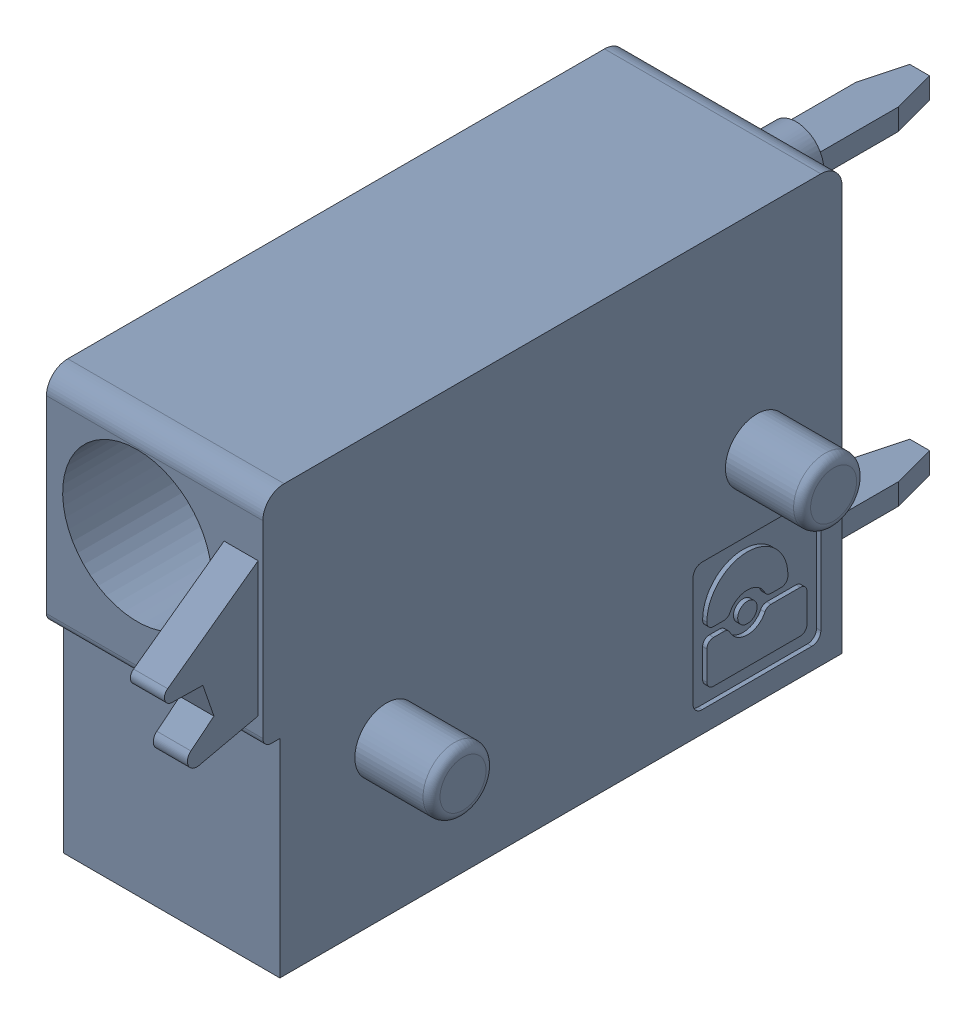
SolidWorks assembly J37, configuration Default. Lengths in mm.
Overall size (6.88 10 19.2).
2 component instances, 1 part files, 0 mates.
Components (placement in the parent):
- 1790348-1: 1790348 [Default] at (111.1251 -7.6199 0) x (0 1 0) z (1 0 0) size (10 19.2 6.88)
  - ffkds-v2-5.08-1: ffkds-v2-5.08 [Default] at (-23.7414 -38.158 -2.54) x (0 -1 0) z (0 0 1) size (19.2 10 6.88)
